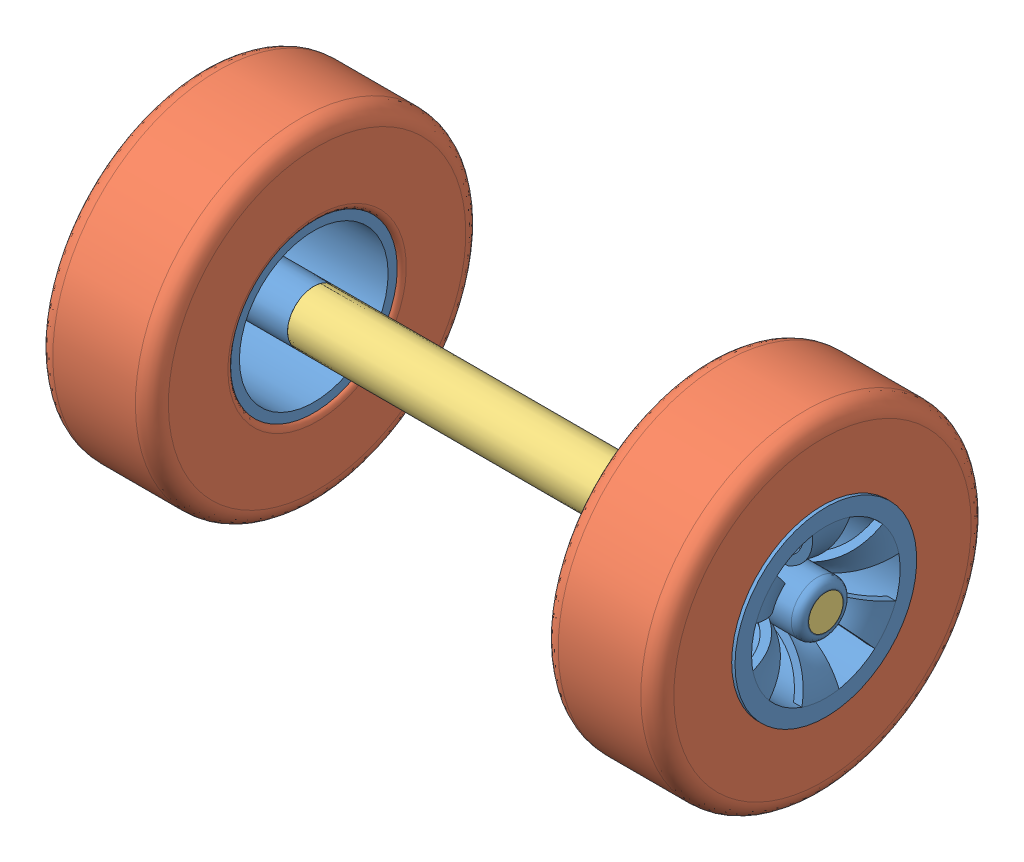
SolidWorks assembly wheel 3, configuration Default. Lengths in mm.
Overall size (96.52 65.42 65.42).
5 component instances, 3 part files, 5 mates.
Components (placement in the parent):
- wheel 1-1: wheel 1 [Default] at (2.2996 14.7083 25.6495) size (17.78 27.94 27.94)
- wheel 2-2: wheel 2 [Default] at (10.6766 14.7083 25.6495) x (0 0.230363 0.973105) z (-1 0 0) size (50.8 50.8 17.78)
- wheel 2-3: wheel 2 [Default] at (-84.8174 14.7083 25.6495) x (0 0.936156 -0.351585) z (1 0 0) size (50.8 50.8 17.78)
- wheel 1-2: wheel 1 [Default] at (-76.4404 14.7083 25.6495) x (-1 0 0) z (0 0.829985 -0.557785) size (17.78 27.94 27.94)
- axle-3: axle [Default] at (-67.5504 14.7083 25.6495) x (0 -0.861406 -0.507917) z (0 -0.507917 0.861406) size (8.08 96.52 8.08)
Mates (geometry in assembly coordinates):
- Lock2: lock: unknown of wheel 1-1; unknown of wheel 2-2
- Lock3: lock: unknown of wheel 2-3; unknown of wheel 1-2
- Coincident1: coincident aligned: circle of wheel 1-2; circle of axel 1-3
- Concentric1: concentric anti-aligned: circle of wheel 1-1; circle of axel 1-3
- Coincident4: coincident anti-aligned: plane of wheel 1-1; plane of axle-3 through (-6.5904 14.7083 25.6495) normal (1 0 0)
